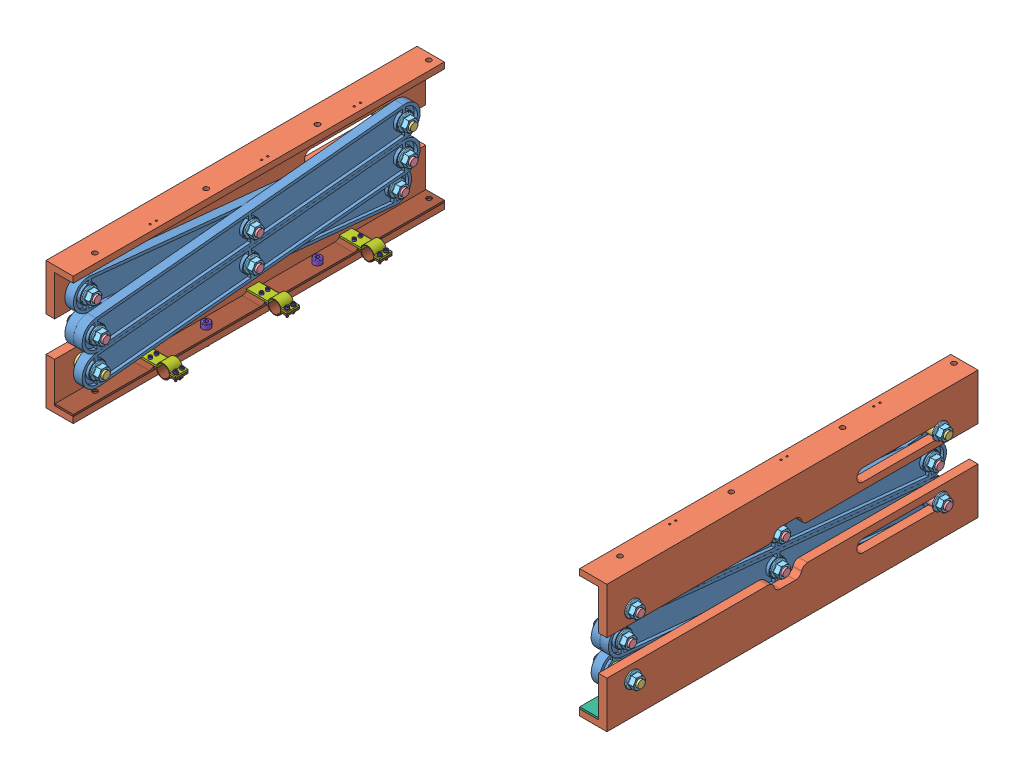
SolidWorks assembly assembly lift_02, configuration Default. Lengths in mm.
Overall size (937 218.53 600).
139 component instances, 11 part files, 117 mates.
Components (placement in the parent):
- links-1: links [Default] at (577.9321 189.0501 -110.4787) x (1 0 0) z (0 0.099312 -0.995056) size (14 49.22 549.22)
- links-2: links [Default] at (577.9321 198.6621 289.7852) x (1 0 0) z (0 -0.099312 0.995056) size (14 49.22 549.22)
- links-3: links [Default] at (591.9321 188.9725 289.7833) x (1 0 0) z (0 0.098927 0.995095) size (14 49.22 549.22)
- links-4: links [Default] at (591.9321 238.5322 289.7929) x (1 0 0) z (0 0.098927 0.995095) size (14 49.22 549.22)
- links-5: links [Default] at (-259.0679 149.1024 289.7756) x (1 0 0) z (0 -0.099312 0.995056) size (14 49.22 549.22)
- links-6: links [Default] at (-273.0679 188.9725 289.7833) x (1 0 0) z (0 0.098927 0.995095) size (14 49.22 549.22)
- links-7: links [Default] at (-273.0679 238.5322 289.7929) x (1 0 0) z (0 0.098927 0.995095) size (14 49.22 549.22)
- links-8: links [Default] at (-259.0679 198.6621 289.7852) x (1 0 0) z (0 -0.099312 0.995056) size (14 49.22 549.22)
- base plate-1: base plate [Default] at (159.4321 90.6405 79.4191) size (907 75 600)
- base plate-2: base plate [Default] at (159.4321 297.1682 79.4191) x (-1 0 0) z (0 0 1) size (907 75 600)
- pin-43-1: pin-43 [Default] at (591.9321 243.4641 -159.106) size (72 20 20)
- pin-43-2: pin-43 [Default] at (-273.0679 144.2482 338.4125) size (72 20 20)
- pin-43-3: pin-43 [Default] at (591.9321 144.2482 338.4125) size (72 20 20)
- pin-43-4: pin-43 [Default] at (-273.0679 243.4641 -159.106) size (72 20 20)
- pin-28-1: pin-28 [Default] at (584.9321 218.636 89.6581) size (58 20 20)
- pin-28-2: pin-28 [Default] at (584.9321 169.0763 89.6485) size (58 20 20)
- pin-28-3: pin-28 [Default] at (598.9321 144.3446 -159.1252) size (58 20 20)
- pin-28-4: pin-28 [Default] at (584.9321 193.9043 -159.1156) size (58 20 20)
- pin-28-5: pin-28 [Default] at (598.9321 243.3676 338.4317) size (58 20 20)
- pin-28-6: pin-28 [Default] at (584.9321 193.8079 338.4221) size (58 20 20)
- hex nuts with flange-fine pitch gb-2: hex nuts with flange-fine pitch gb [GB_HEXAGON_TYPE2 M12X1.25-N] at (624.9321 144.2482 338.4125) x (0 0 -1) z (1 0 0) size (26 26 12)
- hex nuts with flange-fine pitch gb-3: hex nuts with flange-fine pitch gb [GB_HEXAGON_TYPE2 M12X1.25-N] at (610.9321 193.8079 338.4221) x (0 0 -1) z (1 0 0) size (26 26 12)
- hex nuts with flange-fine pitch gb-4: hex nuts with flange-fine pitch gb [GB_HEXAGON_TYPE2 M12X1.25-N] at (624.9321 243.5605 338.4125) x (0 0 -1) z (1 0 0) size (26 26 12)
- hex nuts with flange-fine pitch gb-5: hex nuts with flange-fine pitch gb [GB_HEXAGON_TYPE2 M12X1.25-N] at (610.9321 169.0763 89.6485) x (0 0 -1) z (1 0 0) size (26 26 12)
- hex nuts with flange-fine pitch gb-6: hex nuts with flange-fine pitch gb [GB_HEXAGON_TYPE2 M12X1.25-N] at (610.9321 218.636 89.6581) x (0 0 -1) z (1 0 0) size (26 26 12)
- hex nuts with flange-fine pitch gb-7: hex nuts with flange-fine pitch gb [GB_HEXAGON_TYPE2 M12X1.25-N] at (624.9321 144.3446 -159.1252) x (0 0 -1) z (1 0 0) size (26 26 12)
- hex nuts with flange-fine pitch gb-8: hex nuts with flange-fine pitch gb [GB_HEXAGON_TYPE2 M12X1.25-N] at (610.9321 193.9043 -159.1156) x (0 0 -1) z (1 0 0) size (26 26 12)
- hex nuts with flange-fine pitch gb-9: hex nuts with flange-fine pitch gb [GB_HEXAGON_TYPE2 M12X1.25-N] at (624.9321 243.4641 -159.106) x (0 0 -1) z (1 0 0) size (26 26 12)
- hex nuts with flange-fine pitch gb-10: hex nuts with flange-fine pitch gb [GB_HEXAGON_TYPE2 M12X1.25-N] at (558.9321 144.2482 338.4125) x (0 0 1) z (-1 0 0) size (26 26 12)
- hex nuts with flange-fine pitch gb-11: hex nuts with flange-fine pitch gb [GB_HEXAGON_TYPE2 M12X1.25-N] at (558.9321 193.8079 338.4221) x (0 0 1) z (-1 0 0) size (26 26 12)
- hex nuts with flange-fine pitch gb-12: hex nuts with flange-fine pitch gb [GB_HEXAGON_TYPE2 M12X1.25-N] at (572.9321 243.3676 338.4317) x (0 0 1) z (-1 0 0) size (26 26 12)
- hex nuts with flange-fine pitch gb-13: hex nuts with flange-fine pitch gb [GB_HEXAGON_TYPE2 M12X1.25-N] at (558.9321 218.636 89.6581) x (0 0 1) z (-1 0 0) size (26 26 12)
- hex nuts with flange-fine pitch gb-14: hex nuts with flange-fine pitch gb [GB_HEXAGON_TYPE2 M12X1.25-N] at (558.9321 169.0763 89.6485) x (0 0 1) z (-1 0 0) size (26 26 12)
- hex nuts with flange-fine pitch gb-15: hex nuts with flange-fine pitch gb [GB_HEXAGON_TYPE2 M12X1.25-N] at (558.9321 243.4641 -159.106) x (0 0 1) z (-1 0 0) size (26 26 12)
- hex nuts with flange-fine pitch gb-16: hex nuts with flange-fine pitch gb [GB_HEXAGON_TYPE2 M12X1.25-N] at (558.9321 193.9043 -159.1156) x (0 0 1) z (-1 0 0) size (26 26 12)
- hex nuts with flange-fine pitch gb-17: hex nuts with flange-fine pitch gb [GB_HEXAGON_TYPE2 M12X1.25-N] at (572.9321 144.3446 -159.1252) x (0 0 1) z (-1 0 0) size (26 26 12)
- pin-28-7: pin-28 [Default] at (-266.0679 218.636 89.6581) x (-1 0 0) z (0 0 -1) size (58 20 20)
- pin-28-8: pin-28 [Default] at (-266.0679 169.0763 89.6485) x (-1 0 0) z (0 0 -1) size (58 20 20)
- pin-28-9: pin-28 [Default] at (-280.0679 144.3446 -159.1252) x (-1 0 0) z (0 0 -1) size (58 20 20)
- pin-28-10: pin-28 [Default] at (-266.0679 193.9043 -159.1156) x (-1 0 0) z (0 0 -1) size (58 20 20)
- pin-28-11: pin-28 [Default] at (-280.0679 243.3676 338.4317) x (-1 0 0) z (0 0 -1) size (58 20 20)
- pin-28-12: pin-28 [Default] at (-266.0679 193.8079 338.4221) x (-1 0 0) z (0 0 -1) size (58 20 20)
- hex nuts with flange-fine pitch gb-18: hex nuts with flange-fine pitch gb [GB_HEXAGON_TYPE2 M12X1.25-N] at (-306.0679 144.2482 338.4125) x (0 0 1) z (-1 0 0) size (26 26 12)
- hex nuts with flange-fine pitch gb-19: hex nuts with flange-fine pitch gb [GB_HEXAGON_TYPE2 M12X1.25-N] at (-292.0679 193.8079 338.4221) x (0 0 1) z (-1 0 0) size (26 26 12)
- hex nuts with flange-fine pitch gb-20: hex nuts with flange-fine pitch gb [GB_HEXAGON_TYPE2 M12X1.25-N] at (-306.0679 243.5605 338.4125) x (0 0 1) z (-1 0 0) size (26 26 12)
- hex nuts with flange-fine pitch gb-21: hex nuts with flange-fine pitch gb [GB_HEXAGON_TYPE2 M12X1.25-N] at (-292.0679 169.0763 89.6485) x (0 0 1) z (-1 0 0) size (26 26 12)
- hex nuts with flange-fine pitch gb-22: hex nuts with flange-fine pitch gb [GB_HEXAGON_TYPE2 M12X1.25-N] at (-292.0679 218.636 89.6581) x (0 0 1) z (-1 0 0) size (26 26 12)
- hex nuts with flange-fine pitch gb-23: hex nuts with flange-fine pitch gb [GB_HEXAGON_TYPE2 M12X1.25-N] at (-306.0679 144.3446 -159.1252) x (0 0 1) z (-1 0 0) size (26 26 12)
- hex nuts with flange-fine pitch gb-24: hex nuts with flange-fine pitch gb [GB_HEXAGON_TYPE2 M12X1.25-N] at (-306.0679 243.4641 -159.106) x (0 0 1) z (-1 0 0) size (26 26 12)
- hex nuts with flange-fine pitch gb-25: hex nuts with flange-fine pitch gb [GB_HEXAGON_TYPE2 M12X1.25-N] at (-292.0679 193.9043 -159.1156) x (0 0 1) z (-1 0 0) size (26 26 12)
- hex nuts with flange-fine pitch gb-26: hex nuts with flange-fine pitch gb [GB_HEXAGON_TYPE2 M12X1.25-N] at (-240.0679 144.2482 338.4125) x (0 0 -1) z (1 0 0) size (26 26 12)
- hex nuts with flange-fine pitch gb-27: hex nuts with flange-fine pitch gb [GB_HEXAGON_TYPE2 M12X1.25-N] at (-240.0679 193.8079 338.4221) x (0 0 -1) z (1 0 0) size (26 26 12)
- hex nuts with flange-fine pitch gb-28: hex nuts with flange-fine pitch gb [GB_HEXAGON_TYPE2 M12X1.25-N] at (-254.0679 243.3676 338.4317) x (0 0 -1) z (1 0 0) size (26 26 12)
- hex nuts with flange-fine pitch gb-29: hex nuts with flange-fine pitch gb [GB_HEXAGON_TYPE2 M12X1.25-N] at (-240.0679 218.636 89.6581) x (0 0 -1) z (1 0 0) size (26 26 12)
- hex nuts with flange-fine pitch gb-30: hex nuts with flange-fine pitch gb [GB_HEXAGON_TYPE2 M12X1.25-N] at (-240.0679 169.0763 89.6485) x (0 0 -1) z (1 0 0) size (26 26 12)
- hex nuts with flange-fine pitch gb-31: hex nuts with flange-fine pitch gb [GB_HEXAGON_TYPE2 M12X1.25-N] at (-240.0679 243.4641 -159.106) x (0 0 -1) z (1 0 0) size (26 26 12)
- hex nuts with flange-fine pitch gb-32: hex nuts with flange-fine pitch gb [GB_HEXAGON_TYPE2 M12X1.25-N] at (-240.0679 193.9043 -159.1156) x (0 0 -1) z (1 0 0) size (26 26 12)
- hex nuts with flange-fine pitch gb-33: hex nuts with flange-fine pitch gb [GB_HEXAGON_TYPE2 M12X1.25-N] at (-254.0679 144.3446 -159.1252) x (0 0 -1) z (1 0 0) size (26 26 12)
- 连接-1: 连接 [默认] at (585.6435 101.1405 88.9711) x (1 0 0) z (0 -1 0) size (878.7 600 22)
  - 剪叉-框连接-1: 剪叉-框连接 [默认] at (13.2887 -9.5519 -2.5) size (65.2 600 11)
  - 框连接夹具-1: 框连接夹具 [默认] at (-31.9113 160.4415 -5.5) x (0 0 1) z (0 -1 0) size (11 65.2 20)
  - 框连接夹具-2: 框连接夹具 [默认] at (-31.9113 -19.5585 -5.5) x (0 0 1) z (0 -1 0) size (11 65.2 20)
  - 框连接夹具-3: 框连接夹具 [默认] at (-31.9113 -169.5585 -5.5) x (0 0 1) z (0 -1 0) size (11 65.2 20)
  - hexagon socket head cap screws gb-4: hexagon socket head cap screws gb [GB_FASTENER_SCREWS_HSHCS M3X12-N] at (-47.2028 -184.5585 -12) x (0 0 1) z (-1 0 0) size (15 5.5 5.5)
  - hex nuts, style 1-grades ab gb-8: hex nuts, style 1-grades ab gb [GB_FASTENER_NUT_SNAB1 M3-N] at (-47.2028 -174.5585 -0.1) size (6.35 5.5 2.4)
  - hexagon socket head cap screws gb-11: hexagon socket head cap screws gb [GB_FASTENER_SCREWS_HSHCS M3X12-N] at (-47.2028 -34.5585 -12) x (0 0 1) z (-1 0 0) size (15 5.5 5.5)
  - plain washers-n series-grade a gb-6: plain washers-n series-grade a gb [GB_FASTENER_WASHER_PWNA 3] at (-47.2028 -184.5585 -9) x (0.923728 0.383049 0) z (0 0 -1) size (7 7 0.5)
  - hexagon socket head cap screws gb-3: hexagon socket head cap screws gb [GB_FASTENER_SCREWS_HSHCS M3X12-N] at (-47.2028 -174.5585 -12) x (0 0 1) z (-1 0 0) size (15 5.5 5.5)
  - hexagon socket head cap screws gb-6: hexagon socket head cap screws gb [GB_FASTENER_SCREWS_HSHCS M3X12-N] at (-47.2028 -24.5585 -12) x (0 0 1) z (-1 0 0) size (15 5.5 5.5)
  - hexagon socket head cap screws gb-7: hexagon socket head cap screws gb [GB_FASTENER_SCREWS_HSHCS M3X12-N] at (-47.2028 155.4415 -12) x (0 0 1) z (-1 0 0) size (15 5.5 5.5)
  - hexagon socket head cap screws gb-8: hexagon socket head cap screws gb [GB_FASTENER_SCREWS_HSHCS M3X12-N] at (-47.2028 145.4415 -12) x (0 0 1) z (-1 0 0) size (15 5.5 5.5)
  - hex nuts, style 1-grades ab gb-2: hex nuts, style 1-grades ab gb [GB_FASTENER_NUT_SNAB1 M3-N] at (-47.2028 155.4415 -0.1) size (6.35 5.5 2.4)
  - hex nuts, style 1-grades ab gb-4: hex nuts, style 1-grades ab gb [GB_FASTENER_NUT_SNAB1 M3-N] at (-47.2028 145.4415 -0.1) size (6.35 5.5 2.4)
  - hex nuts, style 1-grades ab gb-5: hex nuts, style 1-grades ab gb [GB_FASTENER_NUT_SNAB1 M3-N] at (-47.2028 -24.5585 -0.1) size (6.35 5.5 2.4)
  - hex nuts, style 1-grades ab gb-6: hex nuts, style 1-grades ab gb [GB_FASTENER_NUT_SNAB1 M3-N] at (-47.2028 -34.5585 -0.1) size (6.35 5.5 2.4)
  - hex nuts, style 1-grades ab gb-7: hex nuts, style 1-grades ab gb [GB_FASTENER_NUT_SNAB1 M3-N] at (-47.2028 -184.5585 -0.1) size (6.35 5.5 2.4)
  - hexagon socket head cap screws gb-9: hexagon socket head cap screws gb [GB_FASTENER_SCREWS_HSHCS M3X12-N] at (-47.2028 -34.5585 -12) x (0 0 1) z (-1 0 0) size (15 5.5 5.5)
  - plain washers-n series-grade a gb-10: plain washers-n series-grade a gb [GB_FASTENER_WASHER_PWNA 3] at (-47.2028 -34.5585 -9) x (0.923728 0.383049 0) z (0 0 -1) size (7 7 0.5)
  - plain washers-n series-grade a gb-12: plain washers-n series-grade a gb [GB_FASTENER_WASHER_PWNA 3] at (-47.2028 -174.5585 -9) x (0.923728 0.383049 0) z (0 0 -1) size (7 7 0.5)
  - plain washers-n series-grade a gb-13: plain washers-n series-grade a gb [GB_FASTENER_WASHER_PWNA 3] at (-47.2028 -24.5585 -9) x (0.923728 0.383049 0) z (0 0 -1) size (7 7 0.5)
  - plain washers-n series-grade a gb-15: plain washers-n series-grade a gb [GB_FASTENER_WASHER_PWNA 3] at (-47.2028 155.4415 -9) x (0.923728 0.383049 0) z (0 0 -1) size (7 7 0.5)
  - 剪叉-框连接 - 副本-1: 剪叉-框连接 - 副本 [默认] at (-835.4113 -9.5519 -2.5) size (65.2 600 11)
  - 框连接夹具-4: 框连接夹具 [默认] at (-820.2113 140.4415 -5.5) x (0 0 1) z (0 1 0) size (11 65.2 20)
  - 框连接夹具-5: 框连接夹具 [默认] at (-820.2113 -39.5585 -5.5) x (0 0 1) z (0 1 0) size (11 65.2 20)
  - 框连接夹具-6: 框连接夹具 [默认] at (-820.2113 -189.5585 -5.5) x (0 0 1) z (0 1 0) size (11 65.2 20)
  - hexagon socket head cap screws gb-13: hexagon socket head cap screws gb [GB_FASTENER_SCREWS_HSHCS M3X12-N] at (-804.9198 -184.5585 -12) x (0 0 1) z (-1 0 0) size (15 5.5 5.5)
  - hex nuts, style 1-grades ab gb-10: hex nuts, style 1-grades ab gb [GB_FASTENER_NUT_SNAB1 M3-N] at (-804.9198 -174.5585 -2.5) x (-1 0 0) z (0 0 -1) size (6.35 5.5 2.4)
  - hexagon socket head cap screws gb-14: hexagon socket head cap screws gb [GB_FASTENER_SCREWS_HSHCS M3X12-N] at (-804.9198 -34.5585 -12) x (0 0 1) z (-1 0 0) size (15 5.5 5.5)
  - plain washers-n series-grade a gb-16: plain washers-n series-grade a gb [GB_FASTENER_WASHER_PWNA 3] at (-804.9198 -184.5585 -8.5) x (-0.923728 0.383049 0) z (0 0 1) size (7 7 0.5)
  - hexagon socket head cap screws gb-15: hexagon socket head cap screws gb [GB_FASTENER_SCREWS_HSHCS M3X12-N] at (-804.9198 -174.5585 -12) x (0 0 1) z (-1 0 0) size (15 5.5 5.5)
  - hexagon socket head cap screws gb-16: hexagon socket head cap screws gb [GB_FASTENER_SCREWS_HSHCS M3X12-N] at (-804.9198 -24.5585 -12) x (0 0 1) z (-1 0 0) size (15 5.5 5.5)
  - hexagon socket head cap screws gb-17: hexagon socket head cap screws gb [GB_FASTENER_SCREWS_HSHCS M3X12-N] at (-804.9198 155.4415 -12) x (0 0 1) z (-1 0 0) size (15 5.5 5.5)
  - hexagon socket head cap screws gb-18: hexagon socket head cap screws gb [GB_FASTENER_SCREWS_HSHCS M3X12-N] at (-804.9198 145.4415 -12) x (0 0 1) z (-1 0 0) size (15 5.5 5.5)
  - hex nuts, style 1-grades ab gb-11: hex nuts, style 1-grades ab gb [GB_FASTENER_NUT_SNAB1 M3-N] at (-804.9198 155.4415 -2.5) x (-1 0 0) z (0 0 -1) size (6.35 5.5 2.4)
  - hex nuts, style 1-grades ab gb-12: hex nuts, style 1-grades ab gb [GB_FASTENER_NUT_SNAB1 M3-N] at (-804.9198 145.4415 -2.5) x (-1 0 0) z (0 0 -1) size (6.35 5.5 2.4)
  - hex nuts, style 1-grades ab gb-13: hex nuts, style 1-grades ab gb [GB_FASTENER_NUT_SNAB1 M3-N] at (-804.9198 -24.5585 -2.5) x (-1 0 0) z (0 0 -1) size (6.35 5.5 2.4)
  - hex nuts, style 1-grades ab gb-14: hex nuts, style 1-grades ab gb [GB_FASTENER_NUT_SNAB1 M3-N] at (-804.9198 -34.5585 -2.5) x (-1 0 0) z (0 0 -1) size (6.35 5.5 2.4)
  - hex nuts, style 1-grades ab gb-15: hex nuts, style 1-grades ab gb [GB_FASTENER_NUT_SNAB1 M3-N] at (-804.9198 -184.5585 -2.5) x (-1 0 0) z (0 0 -1) size (6.35 5.5 2.4)
  - hexagon socket head cap screws gb-19: hexagon socket head cap screws gb [GB_FASTENER_SCREWS_HSHCS M3X12-N] at (-804.9198 -34.5585 -12) x (0 0 1) z (-1 0 0) size (15 5.5 5.5)
  - plain washers-n series-grade a gb-17: plain washers-n series-grade a gb [GB_FASTENER_WASHER_PWNA 3] at (-804.9198 -34.5585 -8.5) x (-0.923728 0.383049 0) z (0 0 1) size (7 7 0.5)
  - plain washers-n series-grade a gb-18: plain washers-n series-grade a gb [GB_FASTENER_WASHER_PWNA 3] at (-804.9198 -174.5585 -8.5) x (-0.923728 0.383049 0) z (0 0 1) size (7 7 0.5)
  - plain washers-n series-grade a gb-19: plain washers-n series-grade a gb [GB_FASTENER_WASHER_PWNA 3] at (-804.9198 -24.5585 -8.5) x (-0.923728 0.383049 0) z (0 0 1) size (7 7 0.5)
  - plain washers-n series-grade a gb-20: plain washers-n series-grade a gb [GB_FASTENER_WASHER_PWNA 3] at (-804.9198 155.4415 -8.5) x (-0.923728 0.383049 0) z (0 0 1) size (7 7 0.5)
  - plain washers-n series-grade a gb-21: plain washers-n series-grade a gb [GB_FASTENER_WASHER_PWNA 3] at (-47.2028 145.4415 -8.5) x (-0.923728 0.383049 0) z (0 0 1) size (7 7 0.5)
- hexagon socket head cap screws gb-2: hexagon socket head cap screws gb [GB_FASTENER_SCREWS_HSHCS M3X25-N] at (579.4321 112.6405 -95.5875) x (0 -1 0) z (0 0 1) size (28 5.5 5.5)
- hexagon socket head cap screws gb-3: hexagon socket head cap screws gb [GB_FASTENER_SCREWS_HSHCS M3X25-N] at (579.4321 112.6405 -85.5875) x (0 -1 0) z (0 0 1) size (28 5.5 5.5)
- hexagon socket head cap screws gb-4: hexagon socket head cap screws gb [GB_FASTENER_SCREWS_HSHCS M3X25-N] at (579.4321 112.6405 54.4125) x (0 -1 0) z (0 0 1) size (28 5.5 5.5)
- hexagon socket head cap screws gb-5: hexagon socket head cap screws gb [GB_FASTENER_SCREWS_HSHCS M3X25-N] at (579.4321 112.6405 64.4125) x (0 -1 0) z (0 0 1) size (28 5.5 5.5)
- hexagon socket head cap screws gb-6: hexagon socket head cap screws gb [GB_FASTENER_SCREWS_HSHCS M3X25-N] at (579.4321 112.6405 234.4125) x (0 -1 0) z (0 0 1) size (28 5.5 5.5)
- hexagon socket head cap screws gb-7: hexagon socket head cap screws gb [GB_FASTENER_SCREWS_HSHCS M3X25-N] at (579.4321 112.6405 244.4125) x (0 -1 0) z (0 0 1) size (28 5.5 5.5)
- hex nuts, style 1-grades ab gb-1: hex nuts, style 1-grades ab gb [GB_FASTENER_NUT_SNAB1 M3-N] at (544.2211 94.378 233.8181) size (6.35 5.5 2.4)
- hex nuts, style 1-grades ab gb-2: hex nuts, style 1-grades ab gb [GB_FASTENER_NUT_SNAB1 M3-N] at (579.4321 88.2405 244.4125) x (1 0 0) z (0 -1 0) size (6.35 5.5 2.4)
- hex nuts, style 1-grades ab gb-3: hex nuts, style 1-grades ab gb [GB_FASTENER_NUT_SNAB1 M3-N] at (579.4321 88.2405 234.4125) x (1 0 0) z (0 -1 0) size (6.35 5.5 2.4)
- hex nuts, style 1-grades ab gb-4: hex nuts, style 1-grades ab gb [GB_FASTENER_NUT_SNAB1 M3-N] at (579.4321 88.2405 64.4125) x (1 0 0) z (0 -1 0) size (6.35 5.5 2.4)
- hex nuts, style 1-grades ab gb-5: hex nuts, style 1-grades ab gb [GB_FASTENER_NUT_SNAB1 M3-N] at (579.4321 88.2405 54.4125) x (1 0 0) z (0 -1 0) size (6.35 5.5 2.4)
- hex nuts, style 1-grades ab gb-6: hex nuts, style 1-grades ab gb [GB_FASTENER_NUT_SNAB1 M3-N] at (579.4321 88.2405 -95.5875) x (1 0 0) z (0 -1 0) size (6.35 5.5 2.4)
- hex nuts, style 1-grades ab gb-7: hex nuts, style 1-grades ab gb [GB_FASTENER_NUT_SNAB1 M3-N] at (579.4321 88.2405 -85.5875) x (1 0 0) z (0 -1 0) size (6.35 5.5 2.4)
- hex nuts, style 1-grades ab gb-9: hex nuts, style 1-grades ab gb [GB_FASTENER_NUT_SNAB1 M8-N] at (583.9321 83.8405 -30.5875) x (1 0 0) z (0 -1 0) size (15.01 13 6.8)
- hex nuts, style 1-grades ab gb-10: hex nuts, style 1-grades ab gb [GB_FASTENER_NUT_SNAB1 M8-N] at (583.9321 83.8405 149.4125) x (1 0 0) z (0 -1 0) size (15.01 13 6.8)
- hexagon socket head cap screws gb-9: hexagon socket head cap screws gb [GB_FASTENER_SCREWS_HSHCS M8X25-N] at (583.9321 111.6405 -30.5875) x (0 -1 0) z (0 0 1) size (33 13 13)
- hexagon socket head cap screws gb-10: hexagon socket head cap screws gb [GB_FASTENER_SCREWS_HSHCS M8X25-N] at (583.9321 111.6405 149.4125) x (0 -1 0) z (0 0 1) size (33 13 13)
- hexagon socket head cap screws gb-19: hexagon socket head cap screws gb [GB_FASTENER_SCREWS_HSHCS M8X25-N] at (583.9321 111.6405 149.4125) x (0 -1 0) z (0 0 1) size (33 13 13)
- hexagon socket head cap screws gb-11: hexagon socket head cap screws gb [GB_FASTENER_SCREWS_HSHCS M3X25-N] at (-260.5679 112.6405 -95.5875) x (0 -1 0) z (0 0 -1) size (28 5.5 5.5)
- hexagon socket head cap screws gb-12: hexagon socket head cap screws gb [GB_FASTENER_SCREWS_HSHCS M3X25-N] at (-260.5679 112.6405 -85.5875) x (0 -1 0) z (0 0 -1) size (28 5.5 5.5)
- hexagon socket head cap screws gb-13: hexagon socket head cap screws gb [GB_FASTENER_SCREWS_HSHCS M3X25-N] at (-260.5679 112.6405 54.4125) x (0 -1 0) z (0 0 -1) size (28 5.5 5.5)
- hexagon socket head cap screws gb-14: hexagon socket head cap screws gb [GB_FASTENER_SCREWS_HSHCS M3X25-N] at (-260.5679 112.6405 64.4125) x (0 -1 0) z (0 0 -1) size (28 5.5 5.5)
- hexagon socket head cap screws gb-15: hexagon socket head cap screws gb [GB_FASTENER_SCREWS_HSHCS M3X25-N] at (-260.5679 112.6405 234.4125) x (0 -1 0) z (0 0 -1) size (28 5.5 5.5)
- hexagon socket head cap screws gb-16: hexagon socket head cap screws gb [GB_FASTENER_SCREWS_HSHCS M3X25-N] at (-260.5679 112.6405 244.4125) x (0 -1 0) z (0 0 -1) size (28 5.5 5.5)
- hex nuts, style 1-grades ab gb-11: hex nuts, style 1-grades ab gb [GB_FASTENER_NUT_SNAB1 M3-N] at (-225.3569 94.378 231.4181) x (-1 0 0) z (0 0 -1) size (6.35 5.5 2.4)
- hex nuts, style 1-grades ab gb-12: hex nuts, style 1-grades ab gb [GB_FASTENER_NUT_SNAB1 M3-N] at (-260.5679 90.6405 244.4125) x (-1 0 0) z (0 1 0) size (6.35 5.5 2.4)
- hex nuts, style 1-grades ab gb-13: hex nuts, style 1-grades ab gb [GB_FASTENER_NUT_SNAB1 M3-N] at (-260.5679 90.6405 234.4125) x (-1 0 0) z (0 1 0) size (6.35 5.5 2.4)
- hex nuts, style 1-grades ab gb-14: hex nuts, style 1-grades ab gb [GB_FASTENER_NUT_SNAB1 M3-N] at (-260.5679 90.6405 64.4125) x (-1 0 0) z (0 1 0) size (6.35 5.5 2.4)
- hex nuts, style 1-grades ab gb-15: hex nuts, style 1-grades ab gb [GB_FASTENER_NUT_SNAB1 M3-N] at (-260.5679 90.6405 54.4125) x (-1 0 0) z (0 1 0) size (6.35 5.5 2.4)
- hex nuts, style 1-grades ab gb-16: hex nuts, style 1-grades ab gb [GB_FASTENER_NUT_SNAB1 M3-N] at (-260.5679 90.6405 -95.5875) x (-1 0 0) z (0 1 0) size (6.35 5.5 2.4)
- hex nuts, style 1-grades ab gb-17: hex nuts, style 1-grades ab gb [GB_FASTENER_NUT_SNAB1 M3-N] at (-260.5679 90.6405 -85.5875) x (-1 0 0) z (0 1 0) size (6.35 5.5 2.4)
- hex nuts, style 1-grades ab gb-18: hex nuts, style 1-grades ab gb [GB_FASTENER_NUT_SNAB1 M8-N] at (-265.0679 90.6405 -30.5875) x (-1 0 0) z (0 1 0) size (15.01 13 6.8)
- hex nuts, style 1-grades ab gb-19: hex nuts, style 1-grades ab gb [GB_FASTENER_NUT_SNAB1 M8-N] at (-265.0679 90.6405 149.4125) x (-1 0 0) z (0 1 0) size (15.01 13 6.8)
- hexagon socket head cap screws gb-17: hexagon socket head cap screws gb [GB_FASTENER_SCREWS_HSHCS M8X25-N] at (-265.0679 111.6405 -30.5875) x (0 -1 0) z (0 0 -1) size (33 13 13)
- hexagon socket head cap screws gb-18: hexagon socket head cap screws gb [GB_FASTENER_SCREWS_HSHCS M8X25-N] at (-265.0679 111.6405 149.4125) x (0 -1 0) z (0 0 -1) size (33 13 13)
Mates (geometry in assembly coordinates):
- Concentric3: concentric aligned: cylinder of links-1 through (562.9321 169.0763 89.6485) axis (1 0 0) radius 10; cylinder of links-3 through (576.9321 169.0763 89.6485) axis (1 0 0) radius 10
- Concentric4: concentric aligned: cylinder of links-5 through (-274.0679 169.0763 89.6485) axis (1 0 0) radius 10; cylinder of links-6 through (-288.0679 169.0763 89.6485) axis (1 0 0) radius 10
- Coincident4: coincident anti-aligned: plane of links-1 through (584.9321 189.0501 -110.4787) normal (1 0 0); plane of links-3 through (584.9321 144.3446 -159.1252) normal (-1 0 0)
- Coincident5: coincident anti-aligned: plane of links-5 through (-266.0679 193.9043 -159.1156) normal (-1 0 0); plane of links-6 through (-266.0679 188.9725 289.7833) normal (1 0 0)
- Concentric5: concentric aligned: cylinder of links-1 through (562.9321 193.9043 -159.1156) axis (1 0 0) radius 10; cylinder of links-4 through (576.9321 193.9043 -159.1156) axis (1 0 0) radius 10
- Coincident8: coincident anti-aligned: plane of links-1 through (584.9321 189.0501 -110.4787) normal (1 0 0); plane of links-4 through (584.9321 193.9043 -159.1156) normal (-1 0 0)
- Concentric6: concentric aligned: cylinder of links-2 through (562.9321 193.8079 338.4221) axis (1 0 0) radius 10; cylinder of links-3 through (576.9321 193.8079 338.4221) axis (1 0 0) radius 10
- Coincident9: coincident anti-aligned: plane of links-2 through (584.9321 198.6621 289.7852) normal (1 0 0); plane of links-4 through (584.9321 193.9043 -159.1156) normal (-1 0 0)
- Concentric8: concentric aligned: cylinder of links-2 through (562.9321 218.636 89.6581) axis (1 0 0) radius 10; cylinder of links-4 through (576.9321 218.636 89.6581) axis (1 0 0) radius 10
- Concentric9: concentric aligned: cylinder of links-5 through (-274.0679 193.9043 -159.1156) axis (1 0 0) radius 10; cylinder of links-7 through (-288.0679 193.9043 -159.1156) axis (1 0 0) radius 10
- Coincident10: coincident anti-aligned: plane of links-5 through (-266.0679 193.9043 -159.1156) normal (-1 0 0); plane of links-7 through (-266.0679 238.5322 289.7929) normal (1 0 0)
- Concentric10: concentric aligned: cylinder of links-6 through (-288.0679 193.8079 338.4221) axis (1 0 0) radius 10; cylinder of links-8 through (-274.0679 193.8079 338.4221) axis (1 0 0) radius 10
- Coincident11: coincident anti-aligned: plane of links-7 through (-266.0679 238.5322 289.7929) normal (1 0 0); plane of links-8 through (-266.0679 243.4641 -159.106) normal (-1 0 0)
- Concentric11: concentric aligned: cylinder of links-7 through (-288.0679 218.636 89.6581) axis (1 0 0) radius 10; cylinder of links-8 through (-274.0679 218.636 89.6581) axis (1 0 0) radius 10
- Parallel3: parallel anti-aligned: line of links-1 through (570.9321 168.7344 340.8564) axis (0 0.099312 -0.995056); line of links-8 through (-252.0679 223.3146 -158.6046) axis (0 -0.099312 0.995056)
- Coincident29: coincident aligned: plane of base plate-1 through (612.9321 90.6405 79.4191) normal (1 0 0); plane of base plate-2 through (612.9321 297.1682 79.4191) normal (1 0 0)
- LimitDistance4: limit distance = 0.1 mm anti-aligned: plane of links-8 through (-257.0679 174.176 287.3413) normal (0 -0.995056 -0.099312); plane of links-5 through (-257.0679 173.5886 292.2195) normal (0 0.995056 0.099312)
- 重合2: coincident aligned: plane of base plate-1 through (159.4321 100.6405 379.4191) normal (0 0 1); plane of base plate-2 through (159.4321 287.1682 379.4191) normal (0 0 1)
- 重合8: coincident anti-aligned: plane of links-6 through (-280.0679 144.3446 -159.1252) normal (-1 0 0); plane of base plate-1 through (-280.0679 90.6405 79.4191) normal (1 0 0)
- 重合14: coincident anti-aligned: plane of links-3 through (598.9321 188.9725 289.7833) normal (1 0 0); plane of base plate-1 through (598.9321 90.6405 79.4191) normal (-1 0 0)
- 同心11: concentric anti-aligned: cylinder of links-1 through (562.9321 144.2482 338.4125) axis (1 0 0) radius 10; cylinder of pin-43-3 through (612.9321 144.2482 338.4125) axis (-1 0 0) radius 10
- 同心21: concentric aligned: cylinder of base plate-1 through (612.9321 144.2482 338.4125) axis (-1 0 0) radius 10; cylinder of pin-43-3 through (612.9321 144.2482 338.4125) axis (-1 0 0) radius 10
- 重合151: coincident aligned: plane of base plate-1 through (612.9321 90.6405 79.4191) normal (1 0 0); circle of pin-43-3
- 同心31: concentric anti-aligned: cylinder of links-2 through (562.9321 243.4641 -159.106) axis (1 0 0) radius 10; cylinder of pin-43-1 through (612.9321 243.4641 -159.106) axis (-1 0 0) radius 10
- 相切11: tangent anti-aligned: plane of base plate-2 through (-337.0679 233.4641 -34.5875) normal (0 1 0); cylinder of pin-43-1 through (612.9321 243.4641 -159.106) axis (-1 0 0) radius 10
- 重合161: coincident aligned: plane of base plate-2 through (612.9321 297.1682 79.4191) normal (1 0 0); plane of pin-43-1 through (612.9321 243.4641 -159.106) normal (1 0 0)
- 同心41: concentric anti-aligned: cylinder of links-5 through (-274.0679 144.2482 338.4125) axis (1 0 0) radius 10; cylinder of pin-43-2 through (-252.0679 144.2482 338.4125) axis (-1 0 0) radius 10
- 同心51: concentric anti-aligned: cylinder of base plate-1 through (-294.0679 144.2482 338.4125) axis (1 0 0) radius 10; cylinder of pin-43-2 through (-252.0679 144.2482 338.4125) axis (-1 0 0) radius 10
- 重合171: coincident aligned: plane of links-5 through (-252.0679 149.1024 289.7756) normal (1 0 0); plane of pin-43-2 through (-252.0679 144.2482 338.4125) normal (1 0 0)
- 同心61: concentric anti-aligned: cylinder of links-8 through (-274.0679 243.4641 -159.106) axis (1 0 0) radius 10; cylinder of pin-43-4 through (-252.0679 243.4641 -159.106) axis (-1 0 0) radius 10
- 相切21: tangent anti-aligned: plane of base plate-2 through (-337.0679 233.4641 -34.5875) normal (0 1 0); cylinder of pin-43-4 through (-252.0679 243.4641 -159.106) axis (-1 0 0) radius 10
- 重合181: coincident aligned: plane of base plate-2 through (-294.0679 297.1682 79.4191) normal (-1 0 0); plane of pin-43-4 through (-294.0679 243.4641 -159.106) normal (-1 0 0)
- 同心71: concentric anti-aligned: cylinder of links-2 through (562.9321 193.8079 338.4221) axis (1 0 0) radius 10; cylinder of pin-28-6 through (598.9321 193.8079 338.4221) axis (-1 0 0) radius 10
- 同心81: concentric anti-aligned: cylinder of links-3 through (576.9321 193.8079 338.4221) axis (1 0 0) radius 10; cylinder of pin-28-6 through (598.9321 193.8079 338.4221) axis (-1 0 0) radius 10
- 重合191: coincident aligned: plane of links-2 through (570.9321 243.4641 -159.106) normal (-1 0 0); plane of pin-28-6 through (570.9321 193.8079 338.4221) normal (-1 0 0)
- 同心91: concentric anti-aligned: cylinder of links-4 through (576.9321 243.3676 338.4317) axis (1 0 0) radius 10; cylinder of pin-28-5 through (612.9321 243.3676 338.4317) axis (-1 0 0) radius 10
- 平行11: parallel aligned: cylinder of base plate-2 through (612.9321 243.5605 338.4125) axis (-1 0 0) radius 10; cylinder of pin-28-5 through (612.9321 243.3676 338.4317) axis (-1 0 0) radius 10
- 重合201: coincident aligned: plane of links-4 through (584.9321 193.9043 -159.1156) normal (-1 0 0); plane of pin-28-5 through (584.9321 243.3676 338.4317) normal (-1 0 0)
- 同心111: concentric anti-aligned: cylinder of links-1 through (562.9321 169.0763 89.6485) axis (1 0 0) radius 10; cylinder of pin-28-2 through (598.9321 169.0763 89.6485) axis (-1 0 0) radius 10
- 同心121: concentric anti-aligned: cylinder of links-3 through (576.9321 169.0763 89.6485) axis (1 0 0) radius 10; cylinder of pin-28-2 through (598.9321 169.0763 89.6485) axis (-1 0 0) radius 10
- 重合211: coincident aligned: plane of links-1 through (570.9321 144.2482 338.4125) normal (-1 0 0); plane of pin-28-2 through (570.9321 169.0763 89.6485) normal (-1 0 0)
- 同心131: concentric anti-aligned: cylinder of links-4 through (576.9321 218.636 89.6581) axis (1 0 0) radius 10; cylinder of pin-28-1 through (598.9321 218.636 89.6581) axis (-1 0 0) radius 10
- 同心141: concentric anti-aligned: cylinder of links-2 through (562.9321 218.636 89.6581) axis (1 0 0) radius 10; cylinder of pin-28-1 through (598.9321 218.636 89.6581) axis (-1 0 0) radius 10
- 重合221: coincident aligned: plane of links-2 through (570.9321 243.4641 -159.106) normal (-1 0 0); plane of pin-28-1 through (570.9321 218.636 89.6581) normal (-1 0 0)
- 同心151: concentric anti-aligned: cylinder of links-3 through (576.9321 144.3446 -159.1252) axis (1 0 0) radius 10; cylinder of pin-28-3 through (612.9321 144.3446 -159.1252) axis (-1 0 0) radius 10
- 重合231: coincident aligned: plane of links-3 through (584.9321 144.3446 -159.1252) normal (-1 0 0); plane of pin-28-3 through (584.9321 144.3446 -159.1252) normal (-1 0 0)
- 相切41: tangent anti-aligned: plane of base plate-1 through (655.9321 134.3446 -34.5875) normal (0 1 0); cylinder of pin-28-3 through (612.9321 144.3446 -159.1252) axis (-1 0 0) radius 10
- 同心171: concentric anti-aligned: cylinder of links-1 through (562.9321 193.9043 -159.1156) axis (1 0 0) radius 10; cylinder of pin-28-4 through (598.9321 193.9043 -159.1156) axis (-1 0 0) radius 10
- 同心181: concentric anti-aligned: cylinder of links-4 through (576.9321 193.9043 -159.1156) axis (1 0 0) radius 10; cylinder of pin-28-4 through (598.9321 193.9043 -159.1156) axis (-1 0 0) radius 10
- 重合241: coincident aligned: plane of links-1 through (570.9321 144.2482 338.4125) normal (-1 0 0); plane of pin-28-4 through (570.9321 193.9043 -159.1156) normal (-1 0 0)
- 同心19: concentric anti-aligned: cylinder of base plate-1 through (612.9321 144.2482 338.4125) axis (-1 0 0) radius 10; cone of hex nuts with flange-fine pitch gb-2 through (612.9321 144.2482 338.4125) axis (1 0 0)
- 重合25: coincident anti-aligned: plane of base plate-1 through (612.9321 90.6405 79.4191) normal (1 0 0); plane of hex nuts with flange-fine pitch gb-2 through (612.9321 135.2482 333.2164) normal (-1 0 0)
- 同心20: concentric aligned: cylinder of links-3 through (576.9321 193.8079 338.4221) axis (1 0 0) radius 10; cone of hex nuts with flange-fine pitch gb-3 through (598.9321 193.8079 338.4221) axis (1 0 0)
- 重合26: coincident anti-aligned: plane of links-3 through (598.9321 188.9725 289.7833) normal (1 0 0); plane of hex nuts with flange-fine pitch gb-3 through (598.9321 184.8079 333.226) normal (-1 0 0)
- 同心21: concentric anti-aligned: cylinder of base plate-2 through (612.9321 243.5605 338.4125) axis (-1 0 0) radius 10; cone of hex nuts with flange-fine pitch gb-4 through (612.9321 243.5605 338.4125) axis (1 0 0)
- 重合27: coincident anti-aligned: plane of base plate-2 through (612.9321 297.1682 79.4191) normal (1 0 0); plane of hex nuts with flange-fine pitch gb-4 through (612.9321 234.5605 333.2164) normal (-1 0 0)
- 同心22: concentric aligned: cylinder of links-3 through (593.9321 169.0763 89.6485) axis (1 0 0) radius 14.0002; cone of hex nuts with flange-fine pitch gb-5 through (598.9321 169.0763 89.6485) axis (1 0 0)
- 重合28: coincident anti-aligned: plane of links-3 through (598.9321 188.9725 289.7833) normal (1 0 0); plane of hex nuts with flange-fine pitch gb-5 through (598.9321 160.0763 84.4523) normal (-1 0 0)
- 同心23: concentric aligned: cylinder of links-4 through (576.9321 218.636 89.6581) axis (1 0 0) radius 10; cone of hex nuts with flange-fine pitch gb-6 through (598.9321 218.636 89.6581) axis (1 0 0)
- 重合29: coincident anti-aligned: plane of links-4 through (598.9321 238.5322 289.7929) normal (1 0 0); plane of hex nuts with flange-fine pitch gb-6 through (598.9321 209.636 84.4619) normal (-1 0 0)
- 同心24: concentric anti-aligned: cylinder of pin-28-3 through (612.9321 144.3446 -159.1252) axis (-1 0 0) radius 10; cone of hex nuts with flange-fine pitch gb-7 through (612.9321 144.3446 -159.1252) axis (1 0 0)
- 重合30: coincident anti-aligned: plane of pin-28-3 through (612.9321 144.3446 -159.1252) normal (1 0 0); plane of hex nuts with flange-fine pitch gb-7 through (612.9321 135.3446 -164.3214) normal (-1 0 0)
- 同心25: concentric aligned: cylinder of links-4 through (576.9321 193.9043 -159.1156) axis (1 0 0) radius 10; cone of hex nuts with flange-fine pitch gb-8 through (598.9321 193.9043 -159.1156) axis (1 0 0)
- 重合31: coincident anti-aligned: plane of links-4 through (598.9321 238.5322 289.7929) normal (1 0 0); plane of hex nuts with flange-fine pitch gb-8 through (598.9321 184.9043 -164.3118) normal (-1 0 0)
- 同心26: concentric anti-aligned: cylinder of pin-43-1 through (612.9321 243.4641 -159.106) axis (-1 0 0) radius 10; cone of hex nuts with flange-fine pitch gb-9 through (612.9321 243.4641 -159.106) axis (1 0 0)
- 重合32: coincident anti-aligned: plane of pin-43-1 through (612.9321 243.4641 -159.106) normal (1 0 0); plane of hex nuts with flange-fine pitch gb-9 through (612.9321 234.4641 -164.3022) normal (-1 0 0)
- 同心27: concentric aligned: cylinder of pin-43-3 through (612.9321 144.2482 338.4125) axis (-1 0 0) radius 10; cone of hex nuts with flange-fine pitch gb-10 through (570.9321 144.2482 338.4125) axis (-1 0 0)
- 重合33: coincident anti-aligned: plane of pin-43-3 through (570.9321 144.2482 338.4125) normal (-1 0 0); plane of hex nuts with flange-fine pitch gb-10 through (570.9321 135.2482 343.6087) normal (1 0 0)
- 同心28: concentric anti-aligned: cylinder of links-2 through (562.9321 193.8079 338.4221) axis (1 0 0) radius 10; cone of hex nuts with flange-fine pitch gb-11 through (570.9321 193.8079 338.4221) axis (-1 0 0)
- 重合34: coincident anti-aligned: plane of links-2 through (570.9321 243.4641 -159.106) normal (-1 0 0); plane of hex nuts with flange-fine pitch gb-11 through (570.9321 184.8079 343.6183) normal (1 0 0)
- 同心29: concentric aligned: cylinder of pin-28-5 through (612.9321 243.3676 338.4317) axis (-1 0 0) radius 10; cone of hex nuts with flange-fine pitch gb-12 through (584.9321 243.3676 338.4317) axis (-1 0 0)
- 重合35: coincident anti-aligned: plane of pin-28-5 through (584.9321 243.3676 338.4317) normal (-1 0 0); plane of hex nuts with flange-fine pitch gb-12 through (584.9321 234.3676 343.6279) normal (1 0 0)
- 同心30: concentric aligned: cylinder of pin-28-1 through (598.9321 218.636 89.6581) axis (-1 0 0) radius 10; cone of hex nuts with flange-fine pitch gb-13 through (570.9321 218.636 89.6581) axis (-1 0 0)
- 重合36: coincident anti-aligned: plane of pin-28-1 through (570.9321 218.636 89.6581) normal (-1 0 0); plane of hex nuts with flange-fine pitch gb-13 through (570.9321 209.636 94.8542) normal (1 0 0)
- 同心31: concentric aligned: cylinder of links-1 through (575.9321 169.0763 89.6485) axis (-1 0 0) radius 14.0002; cone of hex nuts with flange-fine pitch gb-14 through (570.9321 169.0763 89.6485) axis (-1 0 0)
- 重合37: coincident anti-aligned: plane of links-1 through (570.9321 144.2482 338.4125) normal (-1 0 0); plane of hex nuts with flange-fine pitch gb-14 through (570.9321 160.0763 94.8446) normal (1 0 0)
- 同心32: concentric aligned: cylinder of links-2 through (575.9321 243.4641 -159.106) axis (-1 0 0) radius 14; cone of hex nuts with flange-fine pitch gb-15 through (570.9321 243.4641 -159.106) axis (-1 0 0)
- 重合38: coincident anti-aligned: plane of links-2 through (570.9321 243.4641 -159.106) normal (-1 0 0); plane of hex nuts with flange-fine pitch gb-15 through (570.9321 234.4641 -153.9099) normal (1 0 0)
- 同心33: concentric aligned: cylinder of links-1 through (575.9321 193.9043 -159.1156) axis (-1 0 0) radius 14; cone of hex nuts with flange-fine pitch gb-16 through (570.9321 193.9043 -159.1156) axis (-1 0 0)
- 重合39: coincident anti-aligned: plane of links-1 through (570.9321 144.2482 338.4125) normal (-1 0 0); plane of hex nuts with flange-fine pitch gb-16 through (570.9321 184.9043 -153.9195) normal (1 0 0)
- 同心34: concentric aligned: cylinder of pin-28-3 through (612.9321 144.3446 -159.1252) axis (-1 0 0) radius 10; cone of hex nuts with flange-fine pitch gb-17 through (584.9321 144.3446 -159.1252) axis (-1 0 0)
- 重合40: coincident anti-aligned: plane of pin-28-3 through (584.9321 144.3446 -159.1252) normal (-1 0 0); plane of hex nuts with flange-fine pitch gb-17 through (584.9321 135.3446 -153.9291) normal (1 0 0)
- 同心182: concentric aligned: cylinder of base plate-1 through (583.9321 4.6405 329.4125) axis (0 1 0) radius 4; cylinder of 连接-1/剪叉-框连接-1 through (583.9321 100.6405 329.4125) axis (0 1 0) radius 4
- 重合242: coincident anti-aligned: cylinder of base plate-1 through (583.9321 4.6405 -210.5875) axis (0 1 0) radius 4; circle of 连接-1/剪叉-框连接-1
- 重合243: coincident anti-aligned: plane of base plate-1 through (159.4321 100.6405 79.4191) normal (0 1 0); plane of 连接-1/剪叉-框连接-1 through (598.9321 100.6405 79.4191) normal (0 -1 0)
- 同心183: concentric aligned: cylinder of 连接-1/框连接夹具-3 through (579.4321 89.6405 -95.5875) axis (0 1 0) radius 1.5; cylinder of hexagon socket head cap screws gb-2 through (579.4321 84.6405 -95.5875) axis (0 1 0) radius 1.5
- 重合244: coincident anti-aligned: plane of 连接-1/框连接夹具-3 through (553.7321 109.6405 -100.5875) normal (0 1 0); plane of hexagon socket head cap screws gb-2 through (579.4321 109.6405 -95.5875) normal (0 -1 0)
- 同心184: concentric aligned: cylinder of 连接-1/框连接夹具-3 through (579.4321 89.6405 -85.5875) axis (0 1 0) radius 1.5; cylinder of hexagon socket head cap screws gb-3 through (579.4321 84.6405 -85.5875) axis (0 1 0) radius 1.5
- 重合245: coincident anti-aligned: plane of 连接-1/框连接夹具-3 through (553.7321 109.6405 -100.5875) normal (0 1 0); plane of hexagon socket head cap screws gb-3 through (579.4321 109.6405 -85.5875) normal (0 -1 0)
- 同心185: concentric aligned: cylinder of 连接-1/框连接夹具-2 through (579.4321 89.6405 54.4125) axis (0 1 0) radius 1.5; cylinder of hexagon socket head cap screws gb-4 through (579.4321 84.6405 54.4125) axis (0 1 0) radius 1.5
- 重合246: coincident anti-aligned: plane of 连接-1/框连接夹具-2 through (553.7321 109.6405 49.4125) normal (0 1 0); plane of hexagon socket head cap screws gb-4 through (579.4321 109.6405 54.4125) normal (0 -1 0)
- 同心186: concentric aligned: cylinder of 连接-1/框连接夹具-2 through (579.4321 89.6405 64.4125) axis (0 1 0) radius 1.5; cylinder of hexagon socket head cap screws gb-5 through (579.4321 84.6405 64.4125) axis (0 1 0) radius 1.5
- 重合247: coincident anti-aligned: plane of 连接-1/框连接夹具-2 through (553.7321 109.6405 49.4125) normal (0 1 0); plane of hexagon socket head cap screws gb-5 through (579.4321 109.6405 64.4125) normal (0 -1 0)
- 同心187: concentric aligned: cylinder of 连接-1/框连接夹具-1 through (579.4321 89.6405 234.4125) axis (0 1 0) radius 1.5; cylinder of hexagon socket head cap screws gb-6 through (579.4321 84.6405 234.4125) axis (0 1 0) radius 1.5
- 重合248: coincident anti-aligned: plane of 连接-1/框连接夹具-1 through (553.7321 109.6405 229.4125) normal (0 1 0); plane of hexagon socket head cap screws gb-6 through (579.4321 109.6405 234.4125) normal (0 -1 0)
- 同心188: concentric aligned: cylinder of 连接-1/框连接夹具-1 through (579.4321 89.6405 244.4125) axis (0 1 0) radius 1.5; cylinder of hexagon socket head cap screws gb-7 through (579.4321 84.6405 244.4125) axis (0 1 0) radius 1.5
- 重合249: coincident anti-aligned: plane of 连接-1/框连接夹具-1 through (553.7321 109.6405 229.4125) normal (0 1 0); plane of hexagon socket head cap screws gb-7 through (579.4321 109.6405 244.4125) normal (0 -1 0)
- 同心189: concentric anti-aligned: cylinder of hexagon socket head cap screws gb-7 through (579.4321 84.6405 244.4125) axis (0 1 0) radius 1.5; cone of hex nuts, style 1-grades ab gb-2 through (579.4321 90.6405 244.4125) axis (0 -1 0)
- 重合250: coincident anti-aligned: plane of base plate-1 through (159.4321 90.6405 79.4191) normal (0 -1 0); plane of hex nuts, style 1-grades ab gb-2 through (579.4321 90.6405 238.9125) normal (0 1 0)
- 同心190: concentric anti-aligned: cylinder of hexagon socket head cap screws gb-6 through (579.4321 84.6405 234.4125) axis (0 1 0) radius 1.5; cone of hex nuts, style 1-grades ab gb-3 through (579.4321 90.6405 234.4125) axis (0 -1 0)
- 重合251: coincident anti-aligned: plane of base plate-1 through (159.4321 90.6405 79.4191) normal (0 -1 0); plane of hex nuts, style 1-grades ab gb-3 through (579.4321 90.6405 228.9125) normal (0 1 0)
- 同心191: concentric anti-aligned: cylinder of hexagon socket head cap screws gb-5 through (579.4321 84.6405 64.4125) axis (0 1 0) radius 1.5; cone of hex nuts, style 1-grades ab gb-4 through (579.4321 90.6405 64.4125) axis (0 -1 0)
- 重合252: coincident anti-aligned: plane of base plate-1 through (159.4321 90.6405 79.4191) normal (0 -1 0); plane of hex nuts, style 1-grades ab gb-4 through (579.4321 90.6405 58.9125) normal (0 1 0)
- 同心192: concentric anti-aligned: cylinder of hexagon socket head cap screws gb-4 through (579.4321 84.6405 54.4125) axis (0 1 0) radius 1.5; cone of hex nuts, style 1-grades ab gb-5 through (579.4321 90.6405 54.4125) axis (0 -1 0)
- 重合253: coincident anti-aligned: plane of base plate-1 through (159.4321 90.6405 79.4191) normal (0 -1 0); plane of hex nuts, style 1-grades ab gb-5 through (579.4321 90.6405 48.9125) normal (0 1 0)
- 同心193: concentric anti-aligned: cylinder of hexagon socket head cap screws gb-2 through (579.4321 84.6405 -95.5875) axis (0 1 0) radius 1.5; cone of hex nuts, style 1-grades ab gb-6 through (579.4321 90.6405 -95.5875) axis (0 -1 0)
- 重合254: coincident anti-aligned: plane of base plate-1 through (159.4321 90.6405 79.4191) normal (0 -1 0); plane of hex nuts, style 1-grades ab gb-6 through (579.4321 90.6405 -101.0875) normal (0 1 0)
- 同心194: concentric anti-aligned: cylinder of hexagon socket head cap screws gb-3 through (579.4321 84.6405 -85.5875) axis (0 1 0) radius 1.5; cone of hex nuts, style 1-grades ab gb-7 through (579.4321 90.6405 -85.5875) axis (0 -1 0)
- 重合255: coincident anti-aligned: plane of base plate-1 through (159.4321 90.6405 79.4191) normal (0 -1 0); plane of hex nuts, style 1-grades ab gb-7 through (579.4321 90.6405 -91.0875) normal (0 1 0)
- 同心195: concentric anti-aligned: cylinder of base plate-1 through (583.9321 4.6405 -30.5875) axis (0 1 0) radius 4; cone of hex nuts, style 1-grades ab gb-9 through (583.9321 90.6405 -30.5875) axis (0 -1 0)
- 重合256: coincident anti-aligned: plane of base plate-1 through (159.4321 90.6405 79.4191) normal (0 -1 0); plane of hex nuts, style 1-grades ab gb-9 through (591.4377 90.6405 -30.5875) normal (0 1 0)
- 同心196: concentric anti-aligned: cylinder of base plate-1 through (583.9321 4.6405 149.4125) axis (0 1 0) radius 4; cone of hex nuts, style 1-grades ab gb-10 through (583.9321 90.6405 149.4125) axis (0 -1 0)
- 重合257: coincident anti-aligned: plane of base plate-1 through (159.4321 90.6405 79.4191) normal (0 -1 0); plane of hex nuts, style 1-grades ab gb-10 through (591.4377 90.6405 149.4125) normal (0 1 0)
- 同心197: concentric aligned: cylinder of 连接-1/剪叉-框连接-1 through (583.9321 100.6405 -30.5875) axis (0 1 0) radius 4; cylinder of hexagon socket head cap screws gb-9 through (583.9321 78.6405 -30.5875) axis (0 1 0) radius 4
- 重合258: coincident anti-aligned: plane of 连接-1/剪叉-框连接-1 through (598.9321 103.6405 79.4191) normal (0 1 0); plane of hexagon socket head cap screws gb-9 through (583.9321 103.6405 -30.5875) normal (0 -1 0)
- 同心198: concentric aligned: cylinder of 连接-1/剪叉-框连接-1 through (583.9321 100.6405 149.4125) axis (0 1 0) radius 4; cylinder of hexagon socket head cap screws gb-10 through (583.9321 78.6405 149.4125) axis (0 1 0) radius 4
- 重合259: coincident anti-aligned: plane of 连接-1/剪叉-框连接-1 through (598.9321 103.6405 79.4191) normal (0 1 0); plane of hexagon socket head cap screws gb-10 through (583.9321 103.6405 149.4125) normal (0 -1 0)
